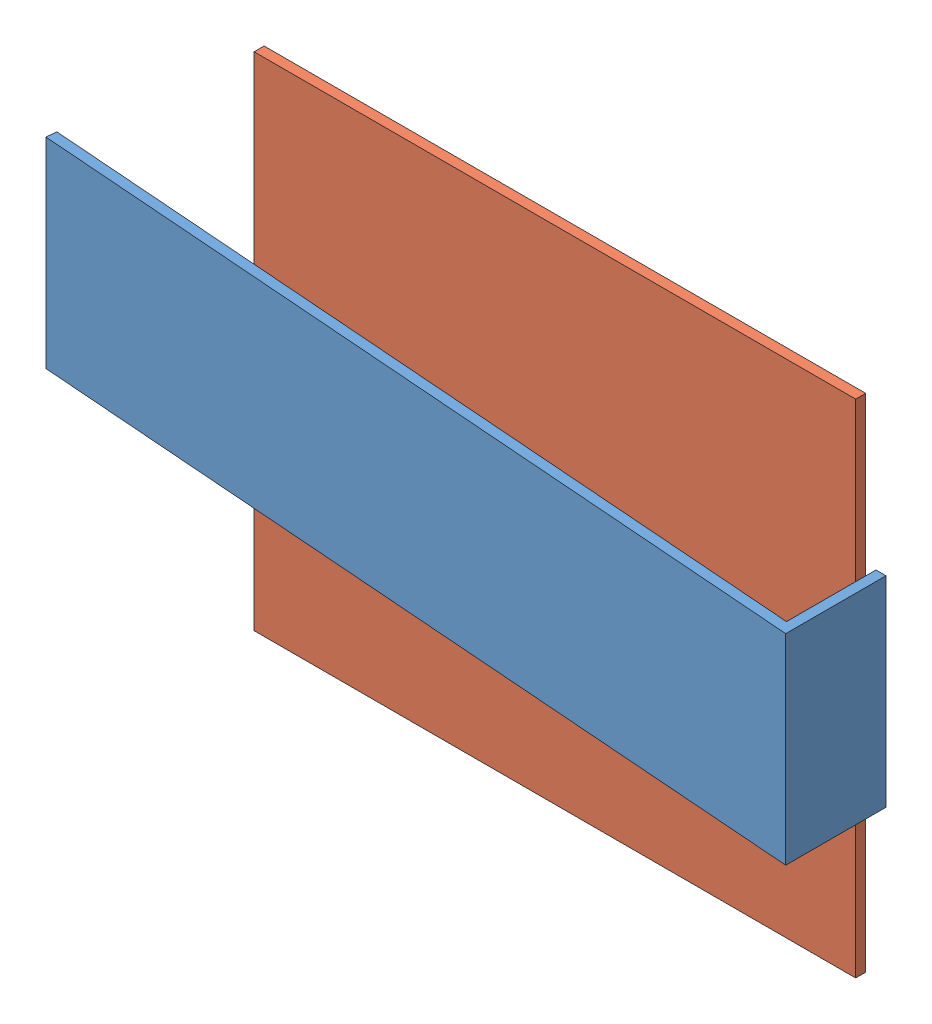
SolidWorks assembly Ensamblaje1, configuration Predeterminado. Lengths in mm.
Overall size (79.77 50 12).
2 component instances, 2 part files, 2 mates.
Components (placement in the parent):
- pletina-1: pletina [Predeterminado] at (39.2872 -6.22 85.7745) size (79.77 20 12)
- tapa_abajo-1: tapa_abajo [Predeterminado] at (-15.9716 -22.1237 77.7931) x (-1 0 0) z (0 -1 0) size (60 4 50)
Mates (geometry in assembly coordinates):
- Coincidente2: coincident anti-aligned: plane of pletina-1 through (38.2872 13.78 84.6964) normal (-1 0 0); plane of tapa_abajo-1 through (38.2872 29.5463 76.7931) normal (1 0 0)
- Concéntrica1: concentric aligned: cylinder of pletina-1 through (33.7872 8.78 79.7745) axis (0 0 -1) radius 2.5; cylinder of tapa_abajo-1 through (33.7872 8.78 76.7931) axis (0 0 -1) radius 2.5
